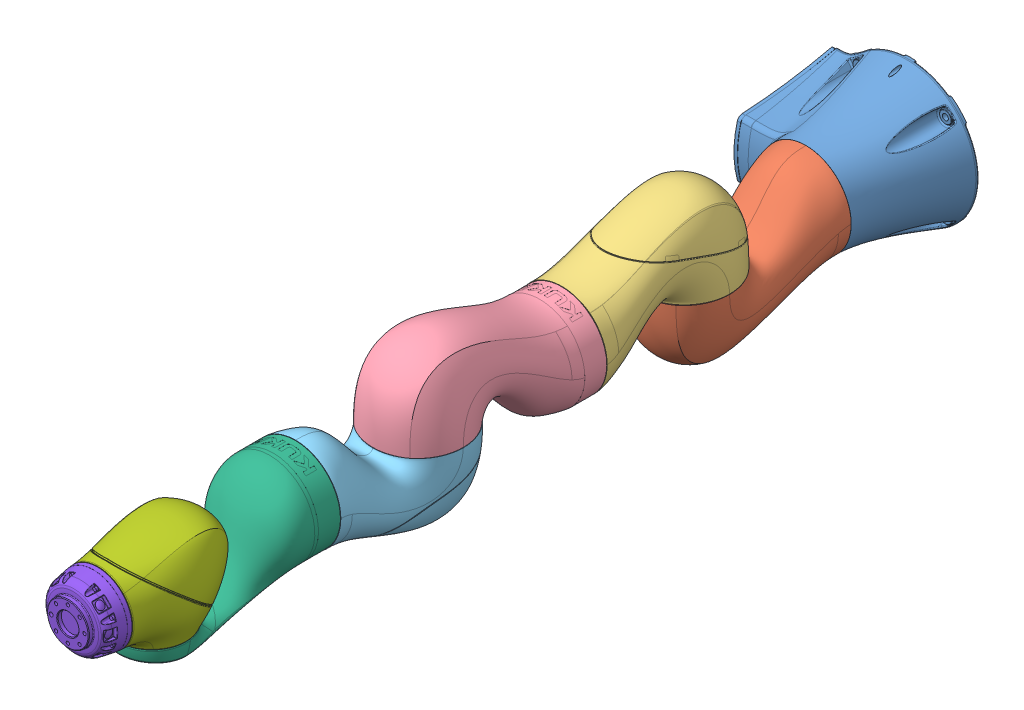
SolidWorks assembly iiwa7, configuration 默认. Lengths in mm.
Overall size (216.96 231.99 1271.47).
8 component instances, 8 part files, 17 mates.
Components (placement in the parent):
- base-1: base [默认] at origin size (216.96 207.92 158.04)
- link1-1: link1 [默认] x (1 -0.000148 0) z (0 0 1) size (136.09 183.99 262.22)
- link2-1: link2 [默认] x (1 -0.000148 0) z (0 0 1) size (137.03 183.96 254.25)
- link3-1: link3 [默认] x (1 0.000992 0) z (0 0 1) size (136.09 183.99 294.72)
- link4-1: link4 [默认] x (1 0.000992 0) z (0 0 1) size (137.03 183.96 254.25)
- link5-1: link5 [默认] at origin size (137.43 170.81 294.47)
- link6-1: link6 [默认] at (0 -0.2 0) size (135.78 137.74 177.69)
- link7-1: link7 [默认] at (0 -0.2 0) x (1 0 0) z (0 0 1) size (103.89 103.89 45)
Mates (geometry in assembly coordinates):
- 重合1: coincident aligned: plane of base-1 through (0 0 0) normal (0 1 0)
- 重合2: coincident aligned: plane of base-1 through (0 0 0) normal (1 0 0)
- 重合3: coincident aligned: plane of base-1 through (0 0 0) normal (0 0 1)
- 同心1: concentric aligned: cylinder of base-1 through (0 0 157) axis (0 0 -1) radius 25; cylinder of link1-1 through (0 0 157) axis (0 0 -1) radius 25
- 重合4: coincident anti-aligned: plane of base-1 through (-75 0 157.5) normal (0 0 1); plane of link1-1 through (0.0111 75 157.5) normal (0 0 -1)
- 同心2: concentric aligned: cylinder of link1-1 through (-0.0001 -0.5 340) axis (-0.000148 -1 0) radius 25; cylinder of link2-1 through (0 0 340) axis (-0.000148 -1 0) radius 25
- 重合6: coincident anti-aligned: plane of link1-1 through (-0.0016 -10.5 340) normal (0.000148 1 0); plane of link2-1 through (-0.0016 -10.5 340) normal (-0.000148 -1 0)
- 同心3: concentric aligned: cylinder of link2-1 through (0 0 524) axis (0 0 -1) radius 25; cylinder of link3-1 through (0 0 524.5) axis (0 0 -1) radius 25
- 重合8: coincident anti-aligned: plane of link2-1 through (0 0 514.5) normal (0 0 1); plane of link3-1 through (0 0 514.5) normal (0 0 -1)
- 同心4: concentric aligned: cylinder of link3-1 through (-0.0005 0.5 740) axis (-0.000992 1 0) radius 25; cylinder of link4-1 through (0 0 740) axis (-0.000992 1 0) radius 25
- 重合10: coincident anti-aligned: plane of link3-1 through (-0.0104 10.5 740) normal (0.000992 -1 0); plane of link4-1 through (-0.0104 10.5 740) normal (-0.000992 1 0)
- 同心5: concentric aligned: cylinder of link4-1 through (0 0 924) axis (0 0 -1) radius 25; cylinder of link5-1 through (0 0 924.5) axis (0 0 -1) radius 25
- 重合11: coincident anti-aligned: plane of link4-1 through (0 0 914.5) normal (0 0 1); plane of link5-1 through (0 0 914.5) normal (0 0 -1)
- 同心6: concentric aligned: cylinder of link5-1 through (0 -60.7 1140) axis (0 -1 0) radius 25; cylinder of link6-1 through (0 -60.2 1140) axis (0 -1 0) radius 25
- 重合12: coincident anti-aligned: plane of link5-1 through (0 -70.7 1140) normal (0 1 0); plane of link6-1 through (0 -70.7 1140) normal (0 -1 0)
- 同心7: concentric anti-aligned: cylinder of link6-1 through (0 -0.2 1220.4) axis (0 0 1) radius 25; cylinder of link7-1 through (0 -0.2 1231) axis (0 0 -1) radius 15.75
- 重合13: coincident anti-aligned: plane of link6-1 through (0 -0.2 1230.9) normal (0 0 1); plane of link7-1 through (0 -0.2 1230.9) normal (0 0 -1)
